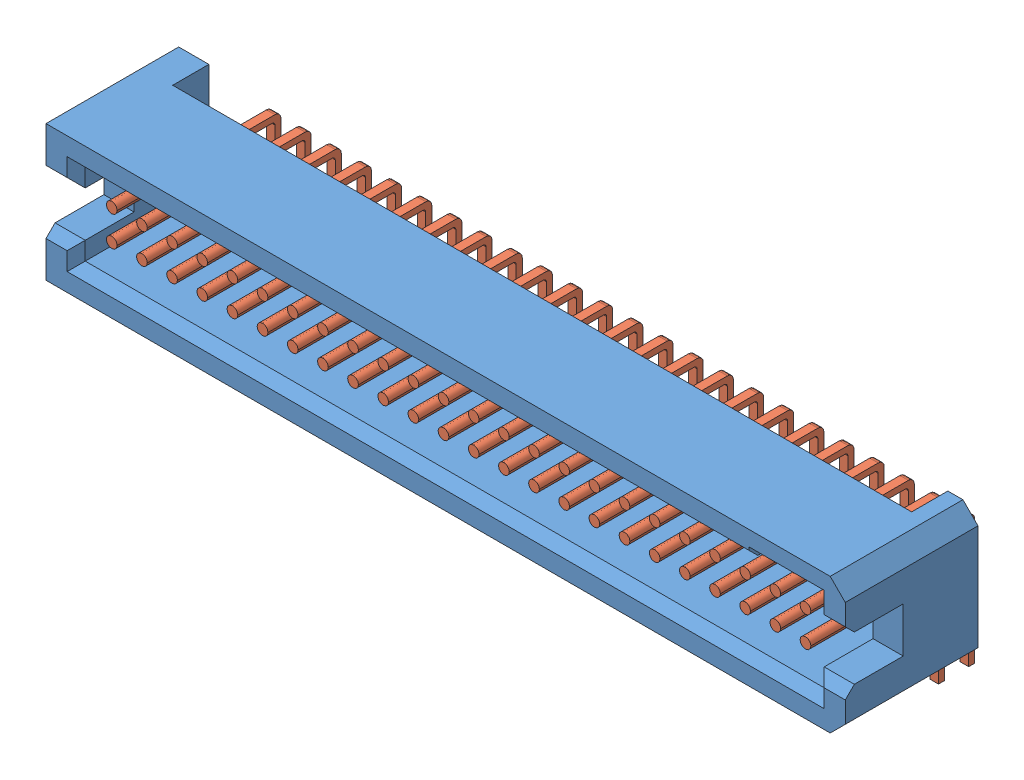
SolidWorks assembly TFC-124-01-F-D-RA, configuration Default. Lengths in mm.
Overall size (33.66 7.62 7.49).
3 component instances, 2 part files, 3 mates.
Components (placement in the parent):
- TFC_124_01_F_D_RA-1: TFC_124_01_F_D_RA [Default] at (0 2.8575 1.143) x (1 0 0) z (0 -1 0) size (33.66 7.49 7.62)
  - _TFC_124_01_L_D_RA_terminal_2-1: _TFC_124_01_L_D_RA_terminal_2 [Default] at origin size (33.66 5.59 5.72)
  - _TFC_124_01_L_D_RA_pins_4-1: _TFC_124_01_L_D_RA_pins_4 [Default] at origin size (30.48 6.95 5.84)
Mates (geometry in assembly coordinates):
- Coincident1: coincident aligned: plane of TFC_124_01_F_D_RA-1 through (0 2.8575 1.143) normal (1 0 0)
- Coincident2: coincident anti-aligned: plane of TFC_124_01_F_D_RA-1/_TFC_124_01_L_D_RA_terminal_2-1 through (-16.8275 0 6.731) normal (0 -1 0)
- Coincident3: coincident anti-aligned: plane of TFC_124_01_F_D_RA-1/_TFC_124_01_L_D_RA_pins_4-1 through (0 2.8575 0) normal (0 0 -1)
